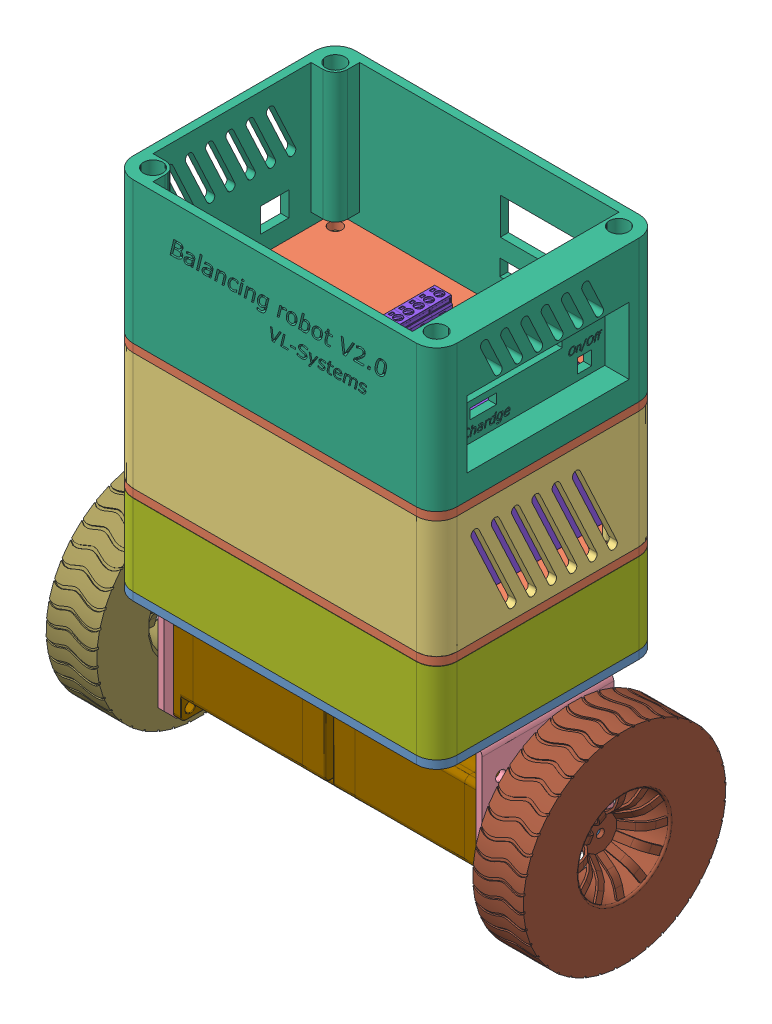
SolidWorks assembly Сборка_Балансира, configuration По умолчанию. Lengths in mm.
Overall size (235.62 287.95 137.58).
17 component instances, 12 part files, 36 mates.
Components (placement in the parent):
- Нижнее основание-1: Нижнее основание [По умолчанию] at origin size (160 4 110)
- Середина-2: Середина [По умолчанию] at (0 44.1616 0) size (160 4 110)
- Стенка-1: Стенка [По умолчанию] at (0 48.1616 0) x (1 0 0) z (0 1 0) size (160 110 58)
- Уголок Шагового Двигателя Nema23-1: Уголок Шагового Двигателя Nema23 [По умолчанию] at (-73 -3 0) x (0 0 1) z (1 0 0) size (65 68 68)
- Уголок Шагового Двигателя Nema23-2: Уголок Шагового Двигателя Nema23 [По умолчанию] at (73 -3 0) x (0 0 -1) z (-1 0 0) size (65 68 68)
- Крепление аккумулятора -1: Крепление аккумулятора  [По умолчанию] at (0 4 0) x (1 0 0) z (0 1 0) size (102.65 62.17 37)
- Середина-3: Середина [По умолчанию] at (0 106.1616 0) size (160 4 110)
- Стенка Raspberry-1: Стенка Raspberry [По умолчанию] at (0 110.1616 0) x (1 0 0) z (0 1 0) size (160 110 70)
- Стенка Аккум-1: Стенка Аккум [По умолчанию] at (0 4 0) x (1 0 0) z (0 1 0) size (160 110 40)
- TB6600 Драйвер шагового двигателя-1: TB6600 Драйвер шагового двигателя [По умолчанию] at (58.5077 63.9116 0.3048) x (-1 0 0) z (0 0 -1) size (71.03 37.69 96)
- TB6600 Драйвер шагового двигателя-2: TB6600 Драйвер шагового двигателя [По умолчанию] at (58.5077 99.6616 0.3048) x (-1 0 0) z (0 0 -1) size (71.03 37.69 96)
- Stepper motor NEMA 23HS7430-1: Stepper motor NEMA 23HS7430 [По умолчанию] at (77 -39 0) x (0 -1 0) z (-1 0 0) size (58.4 56.4 95.6)
- Втулка 8mm-1: Втулка 8mm [По умолчанию] at (97.6 -39 0) x (0 -0.02805 -0.999607) z (1 0 0) size (15.7 13.6 17.73)
- КолесоD100-1: КолесоD100 [По умолчанию] at (99.81 -39 0) x (0 0.85166 -0.524095) z (1 0 0) size (100 100 25)
- Stepper motor NEMA 23HS7430-3: Stepper motor NEMA 23HS7430 [По умолчанию] at (-77 -39 0) x (0 -1 0) z (1 0 0) size (58.4 56.4 95.6)
- Втулка 8mm-3: Втулка 8mm [По умолчанию] at (-97.6 -39 0) x (0 0.02805 0.999607) z (-1 0 0) size (15.7 13.6 17.73)
- Зеркально отразитьКолесоD100-3: Зеркально отразитьКолесоD100 [По умолчанию] at (-99.81 -39 0) x (0 0.85166 -0.524095) z (1 0 0) size (100 100 25)
Mates (geometry in assembly coordinates):
- Параллельность1: parallel aligned: plane of Нижнее основание-1 through (0 4 0) normal (0 1 0); plane of Середина-2 through (0 48.1616 0) normal (0 1 0)
- Концентричный1: concentric aligned: circle of Нижнее основание-1; circle of Середина-2
- Концентричный2: concentric aligned: circle of Нижнее основание-1; circle of Середина-2
- На месте1: in place: plane of ? through (0 39.0861 0) normal (0 1 0); plane of ? through (0 39.0861 0) normal (0 1 0); moOrthogonalPlaneRef_w of ? through (0 39.0861 0) normal (0 1 0); plane of ? through (0 39.0861 0) normal (0 0 -1); plane of ? through (0 39.0861 0) normal (0 1 0); plane of ? through (0 39.0861 0) normal (1 0 0); plane of Середина-2 through (0 48.1616 0) normal (0 1 0); unknown of Стенка-1
- Совпадение4: coincident aligned: plane of Середина-2; plane of Стенка-1
- Совпадение5: coincident aligned: moOrthogonalPlaneRef_w of Середина-2 through (0 48.1616 0) normal (0 0 -1); plane of Стенка-1 through (0 48.1616 0) normal (0 0 -1)
- Совпадение6: coincident anti-aligned: moOrthogonalPlaneRef_w of Середина-2 through (0 48.1616 0) normal (-1 0 0); plane of Стенка-1 through (0 48.1616 0) normal (1 0 0)
- Совпадение7: coincident: plane of Нижнее основание-1 through (0 0 0) normal (0 -1 0); plane of Уголок Шагового Двигателя Nema23-1 through (-80 0 -32.5) normal (0 1 0)
- Совпадение10: coincident: point of Уголок Шагового Двигателя Nema23-1; line of assembly
- На месте2: in place: plane of Нижнее основание-1 through (0 4 0) normal (0 1 0); plane of ? through (0 4 0) normal (0 1 0); plane of Нижнее основание-1 through (0 4 0) normal (0 1 0); plane of ? through (0 4 0) normal (0 0 -1); plane of Нижнее основание-1 through (0 4 0) normal (0 1 0); plane of ? through (0 4 0) normal (1 0 0); plane of Нижнее основание-1 through (0 4 0) normal (0 1 0); unknown of ?
- Совпадение11: coincident aligned: plane of Нижнее основание-1; plane of Крепление аккумулятора -1
- Совпадение12: coincident aligned: moOrthogonalPlaneRef_w of Нижнее основание-1 through (0 4 0) normal (0 0 -1); plane of Крепление аккумулятора -1 through (0 4 0) normal (0 0 -1)
- Совпадение13: coincident anti-aligned: moOrthogonalPlaneRef_w of Нижнее основание-1 through (0 4 0) normal (-1 0 0); plane of Крепление аккумулятора -1 through (0 4 0) normal (1 0 0)
- Совпадение14: coincident anti-aligned: plane of Стенка-1 through (-70 106.1616 -45) normal (0 1 0); plane of Середина-3 through (0 106.1616 0) normal (0 -1 0)
- Концентричный3: concentric aligned: circle of Стенка-1; circle of Середина-3
- Концентричный4: concentric aligned: circle of Стенка-1; circle of Середина-3
- Совпадение15: coincident anti-aligned: plane of Середина-3 through (0 110.1616 0) normal (0 1 0); plane of Стенка Raspberry-1 through (-70 110.1616 -45) normal (0 -1 0)
- Концентричный5: concentric aligned: circle of Середина-3; circle of Стенка Raspberry-1
- Концентричный6: concentric aligned: circle of Середина-3; circle of Стенка Raspberry-1
- Совпадение16: coincident anti-aligned: plane of Нижнее основание-1 through (0 4 0) normal (0 1 0); plane of Стенка Аккум-1 through (-70 4 -45) normal (0 -1 0)
- Концентричный7: concentric aligned: circle of Нижнее основание-1; circle of Стенка Аккум-1
- Концентричный8: concentric aligned: circle of Нижнее основание-1; circle of Стенка Аккум-1
- Совпадение17: coincident anti-aligned: plane of Середина-2 through (0 48.1616 0) normal (0 1 0); plane of TB6600 Драйвер шагового двигателя-1 through (61.0077 48.1616 48.0548) normal (0 -1 0)
- Параллельность2: parallel aligned: plane of Стенка-1 through (-76 106.1616 -39) normal (1 0 0); plane of TB6600 Драйвер шагового двигателя-1 through (61.2577 48.4116 -47.4452) normal (1 0 0)
- Совпадение19: coincident anti-aligned: plane of TB6600 Драйвер шагового двигателя-1 through (61.0077 83.9116 14.5548) normal (0 1 0); plane of TB6600 Драйвер шагового двигателя-2 through (61.0077 83.9116 48.0548) normal (0 -1 0)
- Совпадение20: coincident aligned: plane of TB6600 Драйвер шагового двигателя-1 through (58.7577 74.1616 48.3048) normal (0 0 1); plane of TB6600 Драйвер шагового двигателя-2 through (4.5077 84.1616 48.3048) normal (0 0 1)
- Совпадение21: coincident aligned: plane of TB6600 Драйвер шагового двигателя-1 through (58.5077 83.6616 48.0548) normal (-1 0 0); plane of TB6600 Драйвер шагового двигателя-2 through (58.5077 95.4116 48.0548) normal (-1 0 0)
- Концентричный10: concentric aligned: circle of Уголок Шагового Двигателя Nema23-2; circle of Stepper motor NEMA 23HS7430-1
- Совпадение24: coincident anti-aligned: plane of Уголок Шагового Двигателя Nema23-2 through (77 -68 32.5) normal (-1 0 0); plane of Stepper motor NEMA 23HS7430-1 through (77 -39 0) normal (1 0 0)
- Параллельность3: parallel aligned: plane of Уголок Шагового Двигателя Nema23-2 through (73 -3 -32.5) normal (0 0 -1); plane of Stepper motor NEMA 23HS7430-1 through (13 -22.95 -28.2) normal (0 0 -1)
- Концентричный11: concentric anti-aligned: circle of Stepper motor NEMA 23HS7430-1; circle of Втулка 8mm-1
- Совпадение26: coincident anti-aligned: plane of Stepper motor NEMA 23HS7430-1 through (97.6 -39 0) normal (1 0 0); plane of Втулка 8mm-1 through (97.6 -39 0) normal (-1 0 0)
- Концентричный12: concentric aligned: circle of Втулка 8mm-1; circle of КолесоD100-1
- Параллельность4: parallel anti-aligned: plane of Втулка 8mm-1 through (103.81 -32.3128 -4.1152) normal (0 0.999607 -0.02805); plane of КолесоD100-1 through (103.81 -32.2449 3.6513) normal (0 -0.999607 0.02805)
- Совпадение28: coincident anti-aligned: plane of Втулка 8mm-1 through (103.81 -39 0) normal (1 0 0); plane of КолесоD100-1 through (103.81 -39 0) normal (-1 0 0)
- Совпадение29: coincident: plane of Нижнее основание-1 through (-80 4 0) normal (-1 0 0); plane of Уголок Шагового Двигателя Nema23-1 through (-80 -68 -32.5) normal (-1 0 0)
